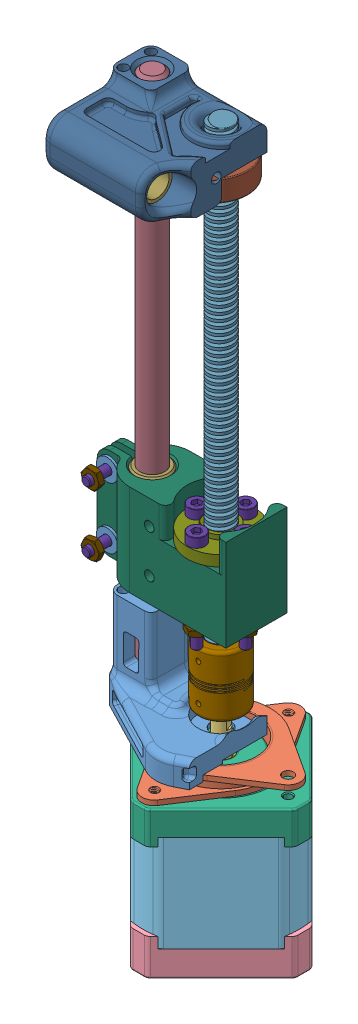
SolidWorks assembly PRUSA 3i horizontal asm, configuration Default. Lengths in mm.
Overall size (67.51 231.9 59.73).
39 component instances, 19 part files, 9 mates.
Components (placement in the parent):
- lead motor assy-1: lead motor assy [Default] at (-0.8403 21.4836 65.5397) size (60.3 83.9 59.73)
  - x motor lead-1: x motor lead [Default] at (1.0016 21.1815 58.4436) size (38.44 32 28.56)
  - Nema 17 Damper v2-1: Nema 17 Damper v2 [Default] at (1.0013 -26.8185 65.4439) x (0.000014 0 -1) z (-1 0 -0.000014) size (52.04 7.74 51.84)
  - 17HM19-2004S-1: 17HM19-2004S [Default] at (-7.0367 -101.7185 75.8822) x (0.703083 0 -0.711108) z (0.711108 0 0.703083) size (42.24 72 42.24)
    - nema17_shaft_17HM19-2004S-1: nema17_shaft_17HM19-2004S [Default] at (13.0746 21 -1.623) x (-0.412738 0 0.91085) z (-0.91085 0 -0.412738) size (5 72 5)
    - nema17_bottom_17HM19-2004S-1: nema17_bottom_17HM19-2004S [Default] at (13.0746 21 -1.623) x (0.999984 0 0.005702) z (-0.005702 0 0.999984) size (42 12 42)
    - nema17_middle_17HM19-2004S-1: nema17_middle_17HM19-2004S [Default] at (13.0746 29.5 -1.623) x (0.999984 0 0.005702) z (-0.005702 0 0.999984) size (42 31.5 42)
    - nema17_top_17HM19-2004S-1: nema17_top_17HM19-2004S [Default] at (13.0746 61 -1.623) x (0.999984 0 0.005702) z (-0.005702 0 0.999984) size (42 12.6 42)
    - radial ball bearing_68_din_DIN 625 - 625 - 8,SI,NC,8_68-1: radial ball bearing_68_din_DIN 625 - 625 - 8,SI,NC,8_68 [Default] at (13.0746 26 -1.623) x (0 -1 0) z (0 0 1) size (5.01 16 16)
    - radial ball bearing_68_din_DIN 625 - 625 - 8,SI,NC,8_68-2: radial ball bearing_68_din_DIN 625 - 625 - 8,SI,NC,8_68 [Default] at (13.0746 67.1 -1.623) x (0 1 0) z (0 0 1) size (5.01 16 16)
    - countersunk flat head cross recess screw_din_ISO 7046-1 - M3 x 30 - Z --- 30N-1: countersunk flat head cross recess screw_din_ISO 7046-1 - M3 x 30 - Z --- 30N [Default] at (28.4859 21.6 13.9651) x (0 1 0) z (0.546944 0 -0.837169) size (30 5.5 5.5)
    - countersunk flat head cross recess screw_din_ISO 7046-1 - M3 x 30 - Z --- 30N-2: countersunk flat head cross recess screw_din_ISO 7046-1 - M3 x 30 - Z --- 30N [Default] at (28.6627 21.6 -17.0344) x (0 1 0) z (0.546944 0 -0.837169) size (30 5.5 5.5)
    - countersunk flat head cross recess screw_din_ISO 7046-1 - M3 x 30 - Z --- 30N-3: countersunk flat head cross recess screw_din_ISO 7046-1 - M3 x 30 - Z --- 30N [Default] at (-2.5136 21.6 13.7883) x (0 1 0) z (0.546944 0 -0.837169) size (30 5.5 5.5)
    - countersunk flat head cross recess screw_din_ISO 7046-1 - M3 x 30 - Z --- 30N-4: countersunk flat head cross recess screw_din_ISO 7046-1 - M3 x 30 - Z --- 30N [Default] at (-2.3368 21.6 -17.2112) x (0 1 0) z (0.546944 0 -0.837169) size (30 5.5 5.5)
  - 5-8 small-1: 5-8 small [Default] at (1.0016 -17.8185 65.4436) x (1 0 0) z (0 1 0) size (15.39 15.39 20)
- x lead idler block-1: x lead idler block [Default] at (-3.2253 161.842 204.8708) x (1 0 0) z (0 0 -1) size (40.45 19.18 38.53)
  - x idler lead mirror-1: x idler lead mirror [Default] at (3.3867 7.1769 80.8876) size (39.97 19.18 36.13)
  - instrument ball bearing_68_iso-1: instrument ball bearing_68_iso [ISO 1224 - 100822 - R,8,SI,NC,8_68] at (2.4627 4.6769 72.4222) x (0 -1 0) z (0 0 1) size (7 22 22)
  - brass sleeve 30mm-1: brass sleeve 30mm [Default] at (3.3867 0.1769 52.8876) x (0 0 1) z (-1 0 0) size (11 11 30)
- liscia da 8 400-1: liscia da 8 400 [Default] at (-22.3386 271.6651 130.9833) x (-0.791136 0 0.611641) z (0 -1 0) size (8 8 167)
- LeadScrew 8mm x 2mmPitch 500-1: LeadScrew 8mm x 2mmPitch 500 [Default] at (0.1614 12.7651 130.9833) x (-0.096506 0 -0.995332) z (0 -1 0) size (9.24 8.22 159.1)
- X CHARIOT ASSY-1: X CHARIOT ASSY [Default] at (-13.6593 122.8824 131.0316) x (1 0 0) z (0 -1 0) size (49.4 23.51 36.69)
  - lead x chariot-1: lead x chariot [Default] at (13.8207 -0.0483 62.5173) size (49.08 20 30.38)
  - brass sleeve 30mm-2: brass sleeve 30mm [Default] at (-8.6793 -0.0483 62.5173) x (0.987351 0.158553 0) z (0 0 1) size (11 11 30)
  - LeadScrew Nut 8mm x 2mmPitch (1)-1: LeadScrew Nut 8mm x 2mmPitch (1) [Default] at (13.8207 -0.0483 69.0173) x (-1 0 0) z (0 0 -1) size (22 22 16.05)
  - socket head cap screw_iso-2: socket head cap screw_iso [ISO 4762 M3 x 30 - 18N] at (5.8207 -0.0483 66.0173) x (0 0 1) z (0.923728 0.383049 0) size (33 5.5 5.5)
  - socket head cap screw_iso-3: socket head cap screw_iso [ISO 4762 M3 x 30 - 18N] at (13.8207 7.9517 66.0173) x (0 0 1) z (0.383049 -0.923728 0) size (33 5.5 5.5)
  - socket head cap screw_iso-4: socket head cap screw_iso [ISO 4762 M3 x 30 - 18N] at (21.8207 -0.0483 66.0173) x (0 0 1) z (-0.923728 -0.383049 0) size (33 5.5 5.5)
  - socket head cap screw_iso-5: socket head cap screw_iso [ISO 4762 M3 x 30 - 18N] at (13.8207 -8.0483 66.0173) x (0 0 1) z (-0.383049 0.923728 0) size (33 5.5 5.5)
  - hex thin nut chamfered gradeab_iso-1: hex thin nut chamfered gradeab_iso [ISO - 4035 - M3 - N] at (21.8207 -0.0483 92.5173) x (-0.923728 -0.383049 0) z (0 0 -1) size (5.5 6.35 1.8)
  - hex thin nut chamfered gradeab_iso-2: hex thin nut chamfered gradeab_iso [ISO - 4035 - M3 - N] at (13.8207 -8.0483 92.5173) x (-0.383049 0.923728 0) z (0 0 -1) size (5.5 6.35 1.8)
  - hex thin nut chamfered gradeab_iso-3: hex thin nut chamfered gradeab_iso [ISO - 4035 - M3 - N] at (5.8207 -0.0483 92.5173) x (0.923728 0.383049 0) z (0 0 -1) size (5.5 6.35 1.8)
  - hex thin nut chamfered gradeab_iso-4: hex thin nut chamfered gradeab_iso [ISO - 4035 - M3 - N] at (13.8207 7.9517 92.5173) x (0.383049 -0.923728 0) z (0 0 -1) size (5.5 6.35 1.8)
  - socket head cap screw_iso-8: socket head cap screw_iso [ISO 4762 M3 x 10 - 10N] at (-19.7187 -2.2811 67.5173) x (0 1 0) z (0.395734 0 0.918365) size (13 5.5 5.5)
  - socket head cap screw_iso-9: socket head cap screw_iso [ISO 4762 M3 x 10 - 10N] at (-19.7187 -2.2811 87.5173) x (0 1 0) z (0.6 0 0.8) size (13 5.5 5.5)
  - plain washer 10673 type snl_iso-3: plain washer 10673 type snl_iso [ISO 10673-3.2-S] at (-19.7187 2.9517 67.5173) x (0 1 0) z (0 0 1) size (0.8 7 7)
  - plain washer 10673 type snl_iso-4: plain washer 10673 type snl_iso [ISO 10673-3.2-S] at (-19.7187 2.9517 87.5173) x (0 1 0) z (0 0 1) size (0.8 7 7)
  - hex thin nut chamfered gradeab_iso-8: hex thin nut chamfered gradeab_iso [ISO - 4035 - M3 - N] at (-19.7187 7.5189 67.5173) x (0.918365 0 -0.395734) z (0 -1 0) size (5.5 6.35 1.8)
  - hex thin nut chamfered gradeab_iso-9: hex thin nut chamfered gradeab_iso [ISO - 4035 - M3 - N] at (-19.7187 7.5189 87.5173) x (0.8 0 -0.6) z (0 -1 0) size (5.5 6.35 1.8)
Mates (geometry in assembly coordinates):
- Coincidente1: coincident aligned: plane of lead motor assy-1/x motor lead-1 through (0.1614 42.6651 123.9833) normal (0 0 -1); plane of x lead idler block-1/x idler lead mirror-1 through (0.1614 154.6651 123.9833) normal (0 0 -1)
- Coincidente2: coincident aligned: plane of lead motor assy-1/x motor lead-1 through (-29.8386 82.6651 137.9833) normal (-1 0 0); plane of x lead idler block-1/x idler lead mirror-1 through (-29.8386 104.6651 137.9833) normal (-1 0 0)
- Distanza1: distance = 130 mm anti-aligned: plane of lead motor assy-1/5-8 small-1 through (0.1614 23.6651 130.9833) normal (0 1 0); plane of x lead idler block-1/x idler lead mirror-1 through (-15.8386 153.6651 88.2062) normal (0 -1 0)
- Concentrico2: concentric aligned: cylinder of lead motor assy-1/x motor lead-1 through (-22.3386 7.6651 130.9833) axis (0 1 0) radius 4.05; cylinder of liscia da 8 400-1 through (-22.3386 -5.6486 130.9833) axis (0 1 0) radius 4
- Coincidente4: coincident anti-aligned: plane of lead motor assy-1/17HM19-2004S-1/nema17_shaft_17HM19-2004S-1 through (0.1614 12.7651 130.9833) normal (0 1 0); plane of LeadScrew 8mm x 2mmPitch 500-1 through (0.1614 12.7651 130.9833) normal (0 -1 0)
- Concentrico4: concentric aligned: cylinder of x lead idler block-1/instrument ball bearing_68_iso-2 through (0.1614 224.3026 130.9833) axis (0 -1 0) radius 4; cylinder of LeadScrew 8mm x 2mmPitch 500-1 through (0.1614 180.9788 130.9833) axis (0 -1 0) radius 4
- Parallelo1: parallel aligned: plane of lead motor assy-1/x motor lead-1 through (0.1614 42.6651 123.9833) normal (0 0 -1); plane of X CHARIOT ASSY-1/lead x chariot-1 through (-29.8386 30.3651 120.9833) normal (0 0 -1)
- Concentrico24: concentric anti-aligned: cylinder of liscia da 8 400-1 through (-22.3386 -5.6486 130.9833) axis (0 1 0) radius 4; cylinder of X CHARIOT ASSY-1/brass sleeve 30mm-2 through (-22.3386 60.3651 130.9833) axis (0 -1 0) radius 4
- LimitDistance1: limit distance = 93.3 mm anti-aligned: plane of x lead idler block-1/x idler lead mirror-1 through (-15.8386 153.6651 88.2062) normal (0 -1 0); plane of X CHARIOT ASSY-1/lead x chariot-1 through (0.1614 60.3651 130.9833) normal (0 1 0)
